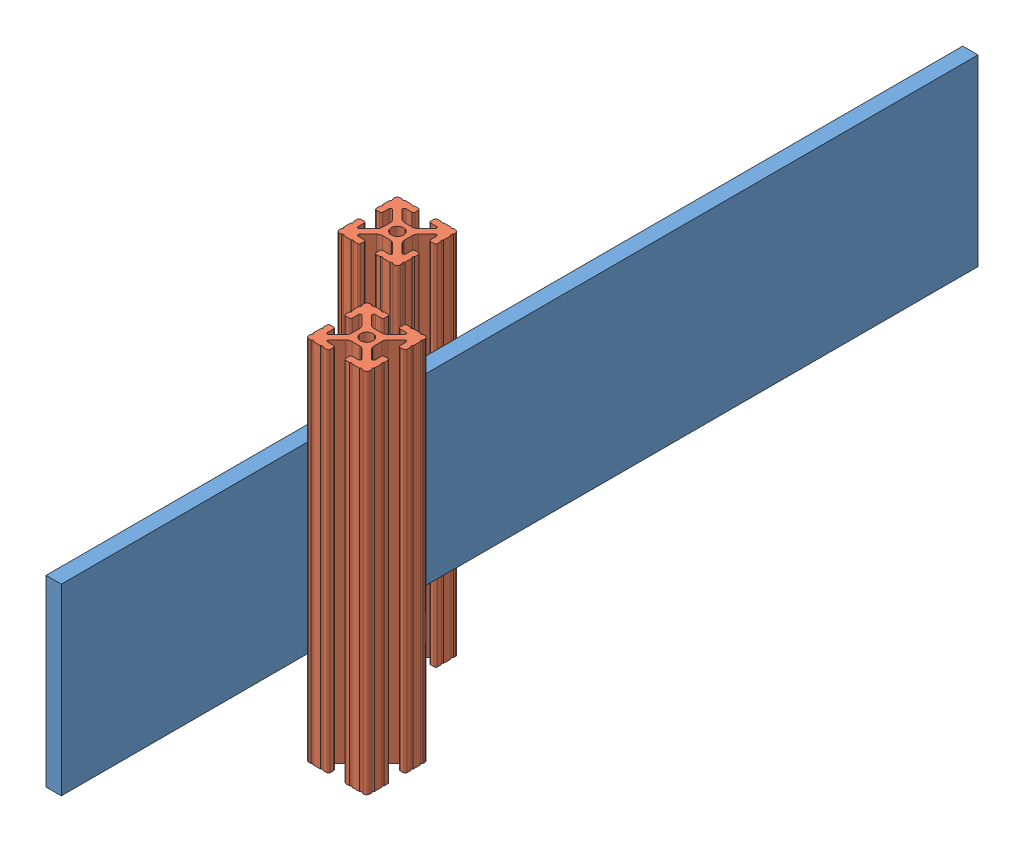
SolidWorks assembly Irby-'Grabber' Fork Proto Final, configuration Default. Lengths in mm.
Overall size (57.15 152.4 381).
3 component instances, 2 part files, 6 mates.
Components (placement in the parent):
- Irby-'Grabber' Fork P1-1: Irby-'Grabber' Fork P1 [Default] at (-414.6254 358.6118 537.0049) size (6.35 76.2 381)
- modifiable_t-slot_bar__6_in_-1: modifiable_t-slot_bar__6_in_ [Default] at (-437.0351 284.753 566.2599) x (0 -1 0) z (0 0 1) size (152.4 25.4 25.4)
- modifiable_t-slot_bar__6_in_-2: modifiable_t-slot_bar__6_in_ [Default] at (-468.7851 284.753 521.8099) x (0 -1 0) z (0 0 1) size (152.4 25.4 25.4)
Mates (geometry in assembly coordinates):
- Coincident1: coincident anti-aligned: plane of Irby-'Grabber' Fork P1-1 through (-408.2754 358.6118 537.0049) normal (1 0 0); plane of modifiable_t-slot_bar__6_in_-1 through (-408.2754 282.4118 625.9049) normal (-1 0 0)
- Distance1: distance = 101.6 mm aligned: plane of Irby-'Grabber' Fork P1-1 through (-408.2754 320.5118 727.5049) normal (0 0 1); plane of modifiable_t-slot_bar__6_in_-1 through (-408.2754 282.4118 625.9049) normal (0 0 1)
- Distance2: distance = 38.1 mm aligned: plane of modifiable_t-slot_bar__6_in_-1 through (-408.2754 282.4118 625.9049) normal (0 -1 0); plane of Irby-'Grabber' Fork P1-1 through (-408.2754 320.5118 346.5049) normal (0 -1 0)
- Coincident4: coincident anti-aligned: plane of Irby-'Grabber' Fork P1-1 through (-414.6254 358.6118 537.0049) normal (-1 0 0); plane of modifiable_t-slot_bar__6_in_-2 through (-414.6254 282.4118 581.4549) normal (1 0 0)
- Distance3: distance = 38.1 mm aligned: plane of modifiable_t-slot_bar__6_in_-2 through (-440.0254 282.4118 581.4549) normal (0 -1 0); plane of Irby-'Grabber' Fork P1-1 through (-408.2754 320.5118 346.5049) normal (0 -1 0)
- Distance4: distance = 19.05 mm anti-aligned: plane of modifiable_t-slot_bar__6_in_-1 through (-408.2754 282.4118 600.5049) normal (0 0 -1); plane of modifiable_t-slot_bar__6_in_-2 through (-440.0254 282.4118 581.4549) normal (0 0 1)
